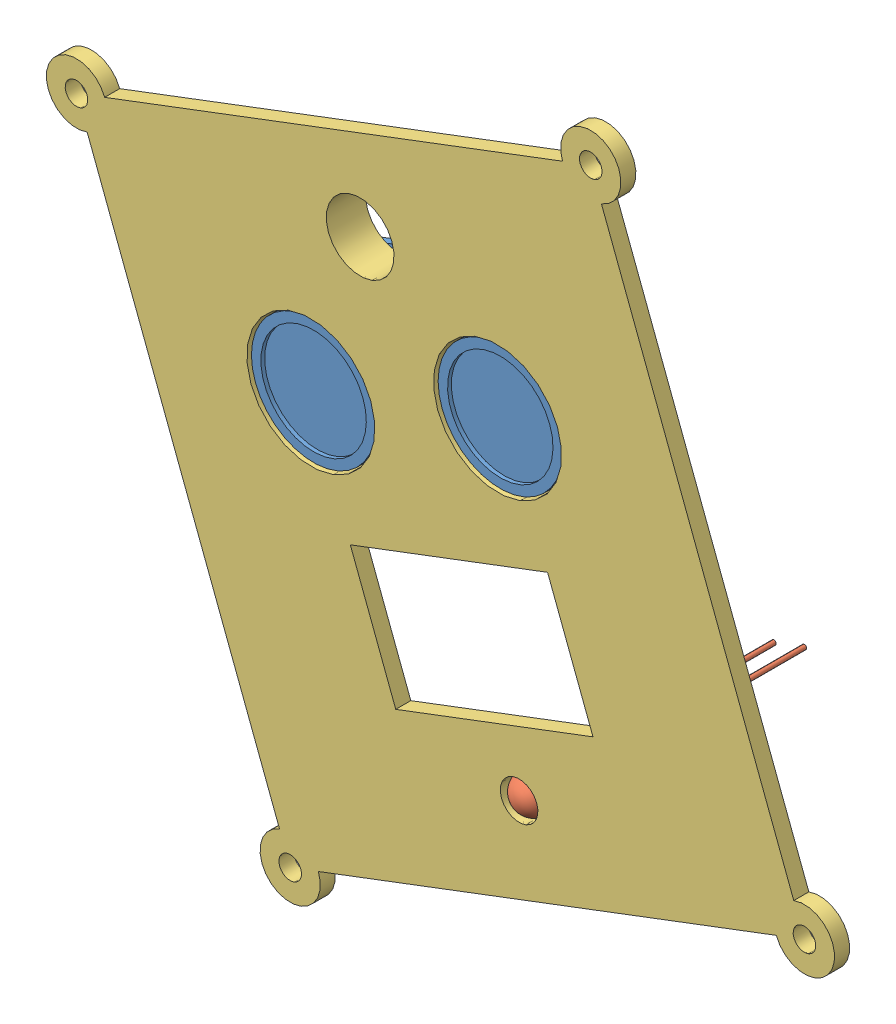
SolidWorks assembly Assem1, configuration Default. Lengths in mm.
Overall size (106.94 111 37.1).
3 component instances, 3 part files, 3 mates.
Components (placement in the parent):
- Ultrassonic sensor HC-SR04-2: Ultrassonic sensor HC-SR04 [Valor predeterminado] at (201.9848 198.2983 188.2778) x (0.935029 0.354571 0) z (0 0 1) size (45 23.45 17)
- LED 5 mm-2: LED 5 mm [Rouge] at (234.7248 177.8293 193.5408) x (-1 0 0) z (0 1 0) size (6 37.1 6)
- top 1-2: top 1 [Default] at (227.8363 195.9381 201.6408) x (-0.935029 -0.354571 0) z (0 0 -1) size (81 88 12)
Mates (geometry in assembly coordinates):
- Concentric1: concentric: circle of Ultrassonic sensor HC-SR04-2; circle of top 1-2
- Coincident1: coincident: circle of LED 5 mm-2; circle of top 1-2
- Concentric3: concentric: circle of Ultrassonic sensor HC-SR04-2; circle of top 1-2
